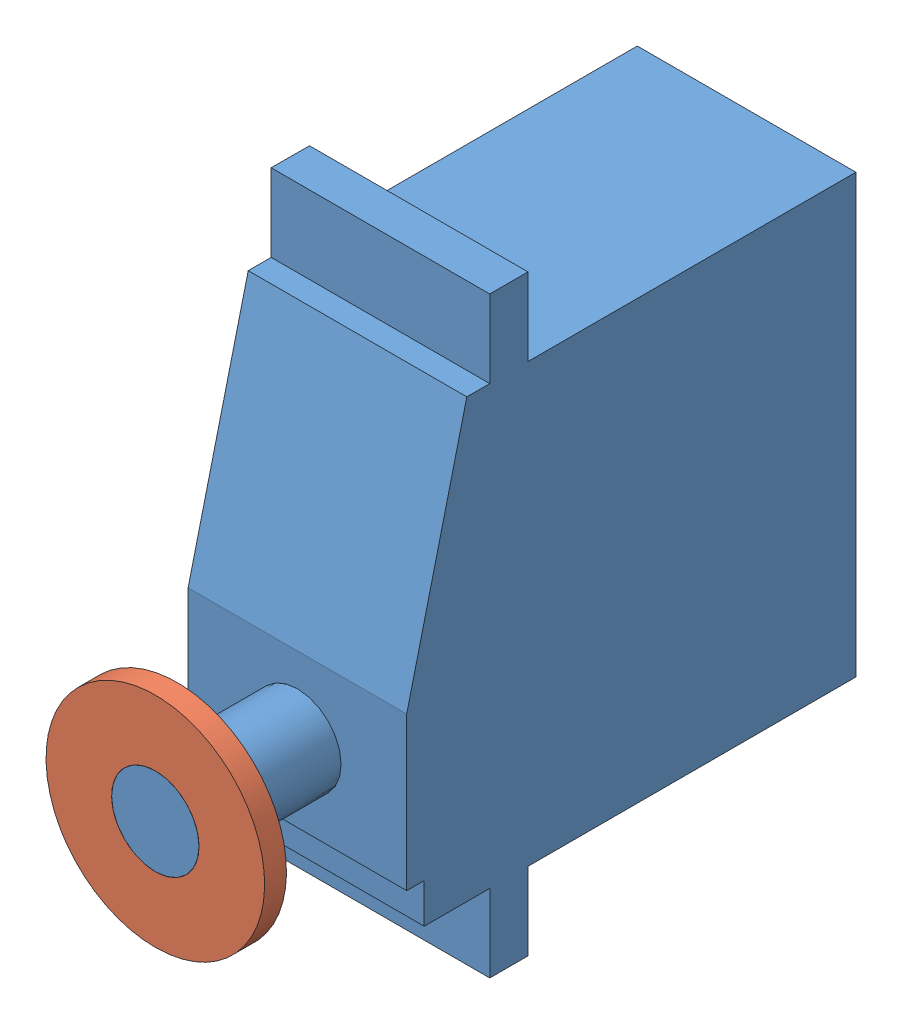
SolidWorks assembly Servo-01, configuration Default. Lengths in mm.
Overall size (27.63 54.2 54.1).
2 component instances, 2 part files, 3 mates.
Components (placement in the parent):
- Servo-Body-2: Servo-Body [Default] at (17.7434 12.3164 23.3438) size (20.01 54.2 54.1)
- Servo-Horn-2: Servo-Horn [Default] at (17.7434 12.3164 75.4438) x (-0.842157 -0.539233 0) z (0 0 1) size (20 20 5.5)
Mates (geometry in assembly coordinates):
- Concentric2: concentric aligned: cylinder of Servo-Body-2 through (17.7434 12.3164 71.4438) axis (0 0 -1) radius 4; cylinder of Servo-Horn-2 through (17.7434 12.3164 77.4438) axis (0 0 -1) radius 4
- Coincident1: coincident aligned: plane of Servo-Body-2 through (17.7434 12.3164 77.4438) normal (0 0 1); plane of Servo-Horn-2 through (17.7434 12.3164 77.4438) normal (0 0 1)
- Coincident2: coincident aligned: plane of Servo-Body-2 through (17.7434 12.3164 77.4438) normal (0 0 1); plane of Servo-Horn-2 through (17.7434 12.3164 77.4438) normal (0 0 1)
